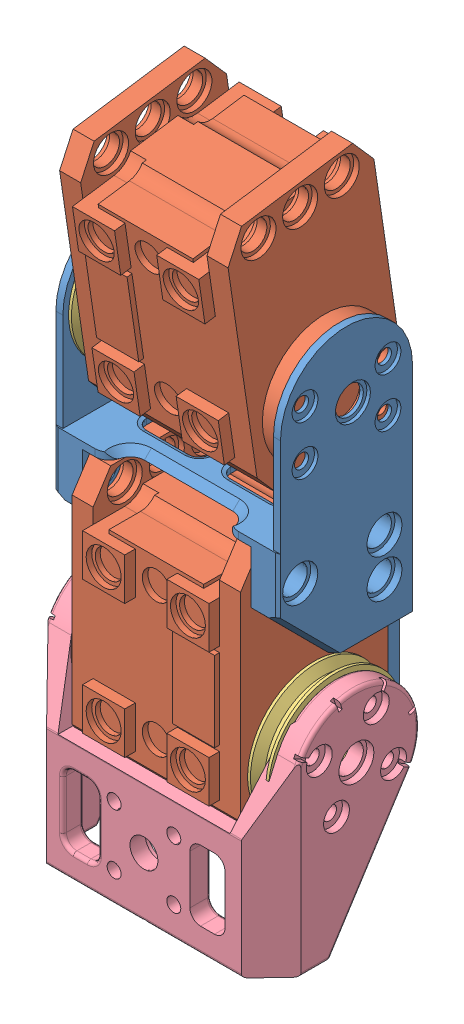
SolidWorks assembly arm, configuration Default. Lengths in mm.
Overall size (36.06 93.78 29.32).
6 component instances, 4 part files, 18 mates.
Components (placement in the parent):
- ext_02-1: ext_02 [Default] at origin size (32 58.53 24)
- XL-1: XL [Default] at (0 31.086 12.3267) x (0 0.145789 -0.989316) z (1 0 0) size (24 36 27)
- wheel-1: wheel [Default] at (-14.25 22.0832 11) x (0 -0.405591 -0.914055) z (0 0.914055 -0.405591) size (19 3 19)
- XL-2: XL [Default] at (0 -11.5 12.5) x (0 0 1) z (-1 0 0) size (24 36 27)
- wheel-2: wheel [Default] at (12.75 -20.6 12.5) x (0 -0.197534 -0.980296) z (0 0.980296 -0.197534) size (19 3 19)
- frm_ext1-1: frm_ext1 [Default] at (0 -34.6355 24.7621) x (1 0 0) z (0 1 0) size (36.06 21.26 31.54)
Mates (geometry in assembly coordinates):
- Coincident1: coordinate: point of ext_02-1
- Concentric1: concentric anti-aligned: circle of ext_02-1; circle of XL-1
- Coincident2: coincident anti-aligned: plane of ext_02-1 through (15 22.5 11.909) normal (-1 0 0); plane of XL-1 through (15 22.0832 11) normal (1 0 0)
- Concentric2: concentric anti-aligned: circle of ext_02-1; circle of wheel-1
- Coincident3: coincident anti-aligned: plane of ext_02-1 through (-15 22.5 11.909) normal (1 0 0); plane of wheel-1 through (-15 22.0832 11) normal (-1 0 0)
- Coincident6: coincident anti-aligned: plane of XL-1 through (-12 31.086 12.3267) normal (-1 0 0); plane of wheel-1 through (-12 22.0832 11) normal (1 0 0)
- Concentric5: concentric aligned: circle of ext_02-1; circle of XL-2
- Coincident10: coincident anti-aligned: plane of ext_02-1 through (-12 0 0) normal (1 0 0); plane of XL-2 through (-12 -11.5 12.5) normal (-1 0 0)
- Coincident11: coincident anti-aligned: plane of ext_02-1 through (12 0 0) normal (-1 0 0); plane of XL-2 through (12 -11.5 12.5) normal (1 0 0)
- Concentric6: concentric anti-aligned: circle of ext_02-1; circle of XL-2
- Coincident14: coincident anti-aligned: plane of XL-2 through (12 -11.5 12.5) normal (1 0 0); plane of wheel-2 through (12 -20.6 12.5) normal (-1 0 0)
- Coincident15: coincident anti-aligned: plane of XL-2 through (12 -11.5 12.5) normal (1 0 0); plane of wheel-2 through (12 -20.6 12.5) normal (-1 0 0)
- Concentric7: concentric anti-aligned: cylinder of XL-2 through (9 -20.6 12.5) axis (1 0 0) radius 2; cylinder of wheel-2 through (12 -20.6 12.5) axis (-1 0 0) radius 2
- Parallel1: parallel anti-aligned: plane of XL-2 through (0 -11.5 12.5) normal (-1 0 0); plane of frm_ext1-1 through (0 -34.6355 24.7621) normal (1 0 0)
- Parallel2: parallel aligned: plane of XL-2 through (0 -11.5 12.5) normal (0 1 0); plane of frm_ext1-1 through (0 -34.6355 24.7621) normal (0 1 0)
- Concentric8: concentric aligned: circle of XL-2; circle of frm_ext1-1
- Coincident19: coincident anti-aligned: plane of wheel-2 through (15 -20.6 12.5) normal (1 0 0); plane of frm_ext1-1 through (15 -43.1355 3.5) normal (-1 0 0)
- LimitAngle1: limit planar angle = 2.995283 rad aligned: plane of assembly through (0 0 0) normal (0 0 1); plane of XL-1 through (0 31.086 12.3267) normal (0 0.145789 -0.989316)
